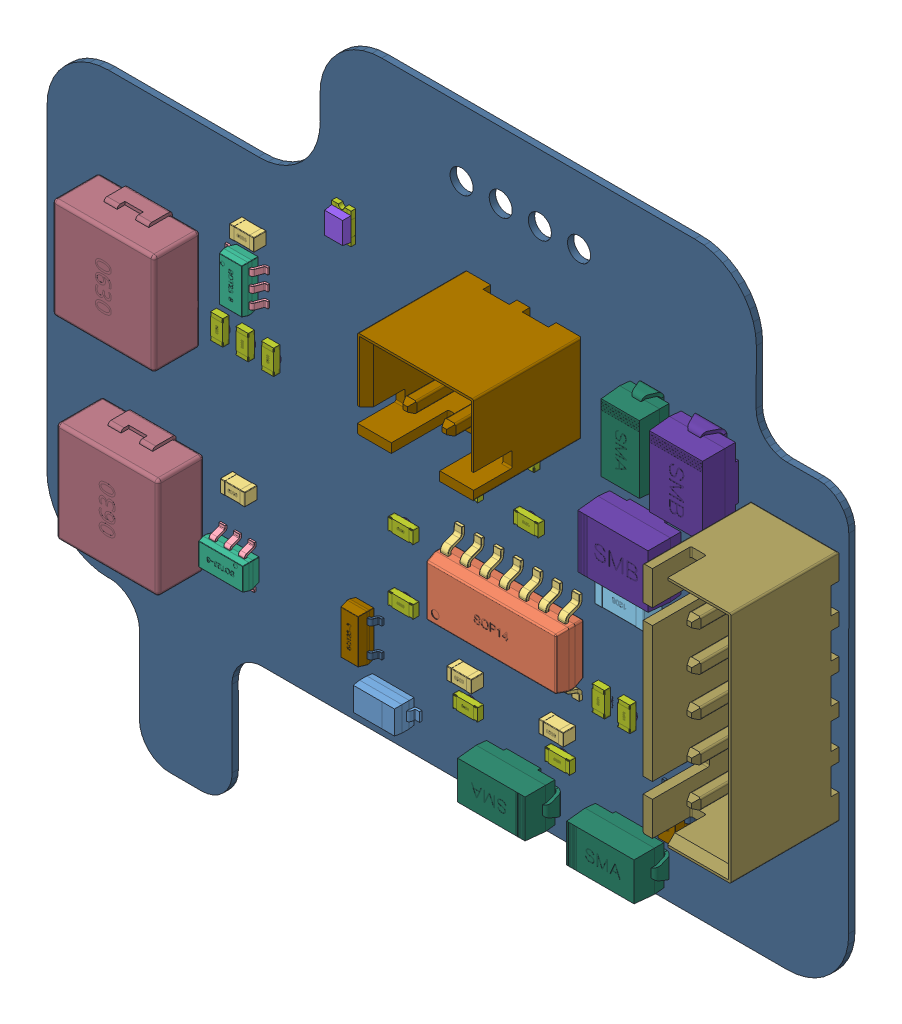
SolidWorks assembly 传感器电路板, configuration 默认. Lengths in mm.
Overall size (52.02 47.02 9.61).
221 component instances, 30 part files, 0 mates.
Components (placement in the parent):
- 传感器电路板.step-1: 传感器电路板.step [Default] at origin size (52.02 47.02 9.61)
  - U3.step-1: U3.step [Default] at origin size (8.7 6.01 1.9)
    - SOP14.step-1: SOP14.step [Default] at (4.699 -2.54 0) x (0 1 0) z (0 0 1) size (6.01 8.7 1.9)
      - LOGO__0.25.step-1: LOGO__0.25.step [Default] at (0.0116 0 0.095) x (0 -1 0) z (0 0 -1) size (0.75 0.87 0.01)
      - SOP14_____.step-1: SOP14_____.step [Default] at origin size (3.6 8.7 1.8)
      - ____1.8_______.step-1: ____1.8_______.step [Default] at (1.8 3.84 1) x (0 1 0) z (0 0 1) size (0.5 1.2 1.1)
      - ____1.8_______.step-2: ____1.8_______.step [Default] at (1.8 2.57 1) x (0 1 0) z (0 0 1) size (0.5 1.2 1.1)
      - ____1.8_______.step-3: ____1.8_______.step [Default] at (1.8 1.3 1) x (0 1 0) z (0 0 1) size (0.5 1.2 1.1)
      - ____1.8_______.step-4: ____1.8_______.step [Default] at (1.8 0.03 1) x (0 1 0) z (0 0 1) size (0.5 1.2 1.1)
      - ____1.8_______.step-5: ____1.8_______.step [Default] at (1.8 -1.24 1) x (0 1 0) z (0 0 1) size (0.5 1.2 1.1)
      - ____1.8_______.step-6: ____1.8_______.step [Default] at (1.8 -2.51 1) x (0 1 0) z (0 0 1) size (0.5 1.2 1.1)
      - ____1.8_______.step-7: ____1.8_______.step [Default] at (1.8 -3.78 1) x (0 1 0) z (0 0 1) size (0.5 1.2 1.1)
      - ____1.8_______.step-8: ____1.8_______.step [Default] at (-1.8 3.84 1) x (0 -1 0) z (0 0 1) size (0.5 1.2 1.1)
      - ____1.8_______.step-9: ____1.8_______.step [Default] at (-1.8 2.57 1) x (0 -1 0) z (0 0 1) size (0.5 1.2 1.1)
      - ____1.8_______.step-10: ____1.8_______.step [Default] at (-1.8 1.3 1) x (0 -1 0) z (0 0 1) size (0.5 1.2 1.1)
      - ____1.8_______.step-11: ____1.8_______.step [Default] at (-1.8 0.03 1) x (0 -1 0) z (0 0 1) size (0.5 1.2 1.1)
      - ____1.8_______.step-12: ____1.8_______.step [Default] at (-1.8 -1.24 1) x (0 -1 0) z (0 0 1) size (0.5 1.2 1.1)
      - ____1.8_______.step-13: ____1.8_______.step [Default] at (-1.8 -2.51 1) x (0 -1 0) z (0 0 1) size (0.5 1.2 1.1)
      - ____1.8_______.step-14: ____1.8_______.step [Default] at (-1.8 -3.78 1) x (0 -1 0) z (0 0 1) size (0.5 1.2 1.1)
  - U2.step-1: U2.step [Default] at origin size (2.81 3 1.18)
    - SOT23-6.step-1: SOT23-6.step [Default] at (-12.954 7.493 0) x (0 -1 0) z (0 0 1) size (3 2.81 1.18)
      - SOT23-5and6_____.step-1: SOT23-5and6_____.step [Default] at (-0.95 -0.8 0.675) x (-1 0 0) z (0 0 1) size (0.4 0.6 0.78)
      - SOT23-5and6_____.step-2: SOT23-5and6_____.step [Default] at (0 -0.8 0.675) x (-1 0 0) z (0 0 1) size (0.4 0.6 0.78)
      - SOT23-5and6_____.step-3: SOT23-5and6_____.step [Default] at (0.95 -0.8 0.675) x (-1 0 0) z (0 0 1) size (0.4 0.6 0.78)
      - SOT23-5and6_____.step-4: SOT23-5and6_____.step [Default] at (-0.95 0.8 0.675) size (0.4 0.6 0.78)
      - SOT23-5and6_____.step-5: SOT23-5and6_____.step [Default] at (0.95 0.8 0.675) size (0.4 0.6 0.78)
      - LOGO__0.15.step-1: LOGO__0.15.step [Default] at (0 -0.0167 0.0485) x (-1 0 0) z (0 0 -1) size (0.45 0.52 0)
      - SOT23-6-0.step-1: SOT23-6-0.step [Default] at origin size (3 1.6 1.1)
      - SOT23-5and6_____.step-6: SOT23-5and6_____.step [Default] at (0 0.8 0.675) size (0.4 0.6 0.78)
  - U1.step-1: U1.step [Default] at origin size (3 2.81 1.18)
    - SOT23-6.step-1: SOT23-6.step [Default] at (-13.589 -8.636 0) x (-1 0 0) z (0 0 1) size (3 2.81 1.18)
      - SOT23-5and6_____.step-1: SOT23-5and6_____.step [Default] at (-0.95 -0.8 0.675) x (-1 0 0) z (0 0 1) size (0.4 0.6 0.78)
      - SOT23-5and6_____.step-2: SOT23-5and6_____.step [Default] at (0 -0.8 0.675) x (-1 0 0) z (0 0 1) size (0.4 0.6 0.78)
      - SOT23-5and6_____.step-3: SOT23-5and6_____.step [Default] at (0.95 -0.8 0.675) x (-1 0 0) z (0 0 1) size (0.4 0.6 0.78)
      - SOT23-5and6_____.step-4: SOT23-5and6_____.step [Default] at (-0.95 0.8 0.675) size (0.4 0.6 0.78)
      - SOT23-5and6_____.step-5: SOT23-5and6_____.step [Default] at (0.95 0.8 0.675) size (0.4 0.6 0.78)
      - LOGO__0.15.step-1: LOGO__0.15.step [Default] at (0 -0.0167 0.0485) x (-1 0 0) z (0 0 -1) size (0.45 0.52 0)
      - SOT23-6-0.step-1: SOT23-6-0.step [Default] at origin size (3 1.6 1.1)
      - SOT23-5and6_____.step-6: SOT23-5and6_____.step [Default] at (0 0.8 0.675) size (0.4 0.6 0.78)
  - R18.step-1: R18.step [Default] at origin size (1.6 0.8 0.4)
    - R_0603.step-1: R_0603.step [Default] at (-2.667 -1.524 0) x (1 0 0) z (0 0 1) size (1.6 0.8 0.4)
      - R_0603-1.step-1: R_0603-1.step [Default] at origin size (1.6 0.8 0.4)
      - LOGO__.step-1: LOGO__.step [Default] at (0.0001 0.0322 -0.0016) x (-1 0 0) z (0 0 -1) size (0.48 0.55 0)
  - R17.step-1: R17.step [Default] at origin size (0.8 1.6 0.4)
    - R_0603.step-1: R_0603.step [Default] at (5.588 6.858 0) x (0 1 0) z (0 0 1) size (1.6 0.8 0.4)
      - R_0603-1.step-1: R_0603-1.step [Default] at origin size (1.6 0.8 0.4)
      - LOGO__.step-1: LOGO__.step [Default] at (0.0001 0.0322 -0.0016) x (-1 0 0) z (0 0 -1) size (0.48 0.55 0)
  - R16.step-1: R16.step [Default] at origin size (1.6 0.8 0.4)
    - R_0603.step-1: R_0603.step [Default] at (5.461 2.921 0) x (1 0 0) z (0 0 1) size (1.6 0.8 0.4)
      - R_0603-1.step-1: R_0603-1.step [Default] at origin size (1.6 0.8 0.4)
      - LOGO__.step-1: LOGO__.step [Default] at (0.0001 0.0322 -0.0016) x (-1 0 0) z (0 0 -1) size (0.48 0.55 0)
  - R15.step-1: R15.step [Default] at origin size (1.6 0.8 0.4)
    - R_0603.step-1: R_0603.step [Default] at (1.524 2.921 0) x (1 0 0) z (0 0 1) size (1.6 0.8 0.4)
      - R_0603-1.step-1: R_0603-1.step [Default] at origin size (1.6 0.8 0.4)
      - LOGO__.step-1: LOGO__.step [Default] at (0.0001 0.0322 -0.0016) x (-1 0 0) z (0 0 -1) size (0.48 0.55 0)
  - R14.step-1: R14.step [Default] at origin size (1.6 0.8 0.4)
    - R_0603.step-1: R_0603.step [Default] at (7.493 -9.398 0) x (1 0 0) z (0 0 1) size (1.6 0.8 0.4)
      - R_0603-1.step-1: R_0603-1.step [Default] at origin size (1.6 0.8 0.4)
      - LOGO__.step-1: LOGO__.step [Default] at (0.0001 0.0322 -0.0016) x (-1 0 0) z (0 0 -1) size (0.48 0.55 0)
  - R13.step-1: R13.step [Default] at origin size (0.8 1.6 0.4)
    - R_0603.step-1: R_0603.step [Default] at (10.16 -4.699 0) x (0 1 0) z (0 0 1) size (1.6 0.8 0.4)
      - R_0603-1.step-1: R_0603-1.step [Default] at origin size (1.6 0.8 0.4)
      - LOGO__.step-1: LOGO__.step [Default] at (0.0001 0.0322 -0.0016) x (-1 0 0) z (0 0 -1) size (0.48 0.55 0)
  - R12.step-1: R12.step [Default] at origin size (0.8 1.6 0.4)
    - R_0603.step-1: R_0603.step [Default] at (11.811 -4.699 0) x (0 -1 0) z (0 0 1) size (1.6 0.8 0.4)
      - R_0603-1.step-1: R_0603-1.step [Default] at origin size (1.6 0.8 0.4)
      - LOGO__.step-1: LOGO__.step [Default] at (0.0001 0.0322 -0.0016) x (-1 0 0) z (0 0 -1) size (0.48 0.55 0)
  - R11.step-1: R11.step [Default] at origin size (1.6 0.8 0.4)
    - R_0603.step-1: R_0603.step [Default] at (-2.667 -5.715 0) x (1 0 0) z (0 0 1) size (1.6 0.8 0.4)
      - R_0603-1.step-1: R_0603-1.step [Default] at origin size (1.6 0.8 0.4)
      - LOGO__.step-1: LOGO__.step [Default] at (0.0001 0.0322 -0.0016) x (-1 0 0) z (0 0 -1) size (0.48 0.55 0)
  - R10.step-1: R10.step [Default] at origin size (0.8 1.6 0.4)
    - R_0603.step-1: R_0603.step [Default] at (13.462 -4.699 0) x (0 -1 0) z (0 0 1) size (1.6 0.8 0.4)
      - R_0603-1.step-1: R_0603-1.step [Default] at origin size (1.6 0.8 0.4)
      - LOGO__.step-1: LOGO__.step [Default] at (0.0001 0.0322 -0.0016) x (-1 0 0) z (0 0 -1) size (0.48 0.55 0)
  - R9.step-1: R9.step [Default] at origin size (1.6 0.8 0.4)
    - R_0603.step-1: R_0603.step [Default] at (1.524 -9.398 0) x (1 0 0) z (0 0 1) size (1.6 0.8 0.4)
      - R_0603-1.step-1: R_0603-1.step [Default] at origin size (1.6 0.8 0.4)
      - LOGO__.step-1: LOGO__.step [Default] at (0.0001 0.0322 -0.0016) x (-1 0 0) z (0 0 -1) size (0.48 0.55 0)
  - R8.step-1: R8.step [Default] at origin size (0.8 1.6 0.4)
    - R_0603.step-1: R_0603.step [Default] at (16.891 -4.699 0) x (0 1 0) z (0 0 1) size (1.6 0.8 0.4)
      - R_0603-1.step-1: R_0603-1.step [Default] at origin size (1.6 0.8 0.4)
      - LOGO__.step-1: LOGO__.step [Default] at (0.0001 0.0322 -0.0016) x (-1 0 0) z (0 0 -1) size (0.48 0.55 0)
  - R7.step-1: R7.step [Default] at origin size (0.8 1.6 0.4)
    - R_0603.step-1: R_0603.step [Default] at (15.24 -4.699 0) x (0 1 0) z (0 0 1) size (1.6 0.8 0.4)
      - R_0603-1.step-1: R_0603-1.step [Default] at origin size (1.6 0.8 0.4)
      - LOGO__.step-1: LOGO__.step [Default] at (0.0001 0.0322 -0.0016) x (-1 0 0) z (0 0 -1) size (0.48 0.55 0)
  - R6.step-1: R6.step [Default] at origin size (0.8 1.6 0.4)
    - R_0603.step-1: R_0603.step [Default] at (-14.605 3.81 0) x (0 -1 0) z (0 0 1) size (1.6 0.8 0.4)
      - R_0603-1.step-1: R_0603-1.step [Default] at origin size (1.6 0.8 0.4)
      - LOGO__.step-1: LOGO__.step [Default] at (0.0001 0.0322 -0.0016) x (-1 0 0) z (0 0 -1) size (0.48 0.55 0)
  - R5.step-1: R5.step [Default] at origin size (0.8 1.6 0.4)
    - R_0603.step-1: R_0603.step [Default] at (-12.954 3.81 0) x (0 -1 0) z (0 0 1) size (1.6 0.8 0.4)
      - R_0603-1.step-1: R_0603-1.step [Default] at origin size (1.6 0.8 0.4)
      - LOGO__.step-1: LOGO__.step [Default] at (0.0001 0.0322 -0.0016) x (-1 0 0) z (0 0 -1) size (0.48 0.55 0)
  - R4.step-1: R4.step [Default] at origin size (0.8 1.6 0.4)
    - R_0603.step-1: R_0603.step [Default] at (-11.303 3.81 0) x (0 -1 0) z (0 0 1) size (1.6 0.8 0.4)
      - R_0603-1.step-1: R_0603-1.step [Default] at origin size (1.6 0.8 0.4)
      - LOGO__.step-1: LOGO__.step [Default] at (0.0001 0.0322 -0.0016) x (-1 0 0) z (0 0 -1) size (0.48 0.55 0)
  - R3.step-1: R3.step [Default] at origin size (1.6 0.8 0.4)
    - R_0603.step-1: R_0603.step [Default] at (-16.256 -5.969 -0.4115) x (1 0 0) z (0 0 -1) size (1.6 0.8 0.4)
      - R_0603-1.step-1: R_0603-1.step [Default] at origin size (1.6 0.8 0.4)
      - LOGO__.step-1: LOGO__.step [Default] at (0.0001 0.0322 -0.0016) x (-1 0 0) z (0 0 -1) size (0.48 0.55 0)
  - R2.step-1: R2.step [Default] at origin size (1.6 0.8 0.4)
    - R_0603.step-1: R_0603.step [Default] at (-16.256 -7.747 -0.4115) x (1 0 0) z (0 0 -1) size (1.6 0.8 0.4)
      - R_0603-1.step-1: R_0603-1.step [Default] at origin size (1.6 0.8 0.4)
      - LOGO__.step-1: LOGO__.step [Default] at (0.0001 0.0322 -0.0016) x (-1 0 0) z (0 0 -1) size (0.48 0.55 0)
  - R1.step-1: R1.step [Default] at origin size (1.6 0.8 0.4)
    - R_0603.step-1: R_0603.step [Default] at (-16.256 -9.652 -0.4115) x (-1 0 0) z (0 0 -1) size (1.6 0.8 0.4)
      - R_0603-1.step-1: R_0603-1.step [Default] at origin size (1.6 0.8 0.4)
      - LOGO__.step-1: LOGO__.step [Default] at (0.0001 0.0322 -0.0016) x (-1 0 0) z (0 0 -1) size (0.48 0.55 0)
  - Q2.step-1: Q2.step [Default] at origin size (2.4 3 1.05)
    - SOT23-3.step-1: SOT23-3.step [Default] at (15.24 -8.382 0) x (0 -1 0) z (0 0 1) size (3 2.4 1.05)
      - SOT23-3-2.step-1: SOT23-3-2.step [Default] at origin size (3 1.3 1)
      - SOT23-3_____.step-1: SOT23-3_____.step [Default] at (0 0.5461 0.475) size (0.4 0.65 0.55)
      - SOT23-3_____.step-2: SOT23-3_____.step [Default] at (-0.95 -0.5461 0.475) x (-1 0 0) z (0 0 1) size (0.4 0.65 0.55)
      - SOT23-3_____.step-3: SOT23-3_____.step [Default] at (0.95 -0.5461 0.475) x (-1 0 0) z (0 0 1) size (0.4 0.65 0.55)
      - LOGO__0.15-3.step-1: LOGO__0.15-3.step [Default] at (0 -0.0163 0.0485) x (-1 0 0) z (0 0 -1) size (0.45 0.52 0)
  - Q1.step-1: Q1.step [Default] at origin size (2.4 3 1.05)
    - SOT23-3.step-1: SOT23-3.step [Default] at (-5.334 -8.509 0) x (0 1 0) z (0 0 1) size (3 2.4 1.05)
      - SOT23-3-2.step-1: SOT23-3-2.step [Default] at origin size (3 1.3 1)
      - SOT23-3_____.step-1: SOT23-3_____.step [Default] at (0 0.5461 0.475) size (0.4 0.65 0.55)
      - SOT23-3_____.step-2: SOT23-3_____.step [Default] at (-0.95 -0.5461 0.475) x (-1 0 0) z (0 0 1) size (0.4 0.65 0.55)
      - SOT23-3_____.step-3: SOT23-3_____.step [Default] at (0.95 -0.5461 0.475) x (-1 0 0) z (0 0 1) size (0.4 0.65 0.55)
      - LOGO__0.15-3.step-1: LOGO__0.15-3.step [Default] at (0 -0.0163 0.0485) x (-1 0 0) z (0 0 -1) size (0.45 0.52 0)
  - P2.step-1: P2.step [Default] at origin size (5.7 15.16 9.5)
    - XH2.54-5P.step-1: XH2.54-5P.step [Default] at (22.098 -1.524 0.03) x (0 1 0) z (1 0 0) size (15.16 9.5 5.7)
      - LOGO__-4.step-1: LOGO__-4.step [Default] at (-1.7013 -0.001 0) x (0 0 1) z (0 -1 0) size (0.9 1.04 0.01)
      - XH2.54-5P-5.step-1: XH2.54-5P-5.step [Default] at origin size (15.16 9.5 5.7)
  - L2.step-1: L2.step [Default] at origin size (6.6 6.95 3.03)
    - SMD-0630.step-1: SMD-0630.step [Default] at (-19.304 5.207 0) x (0 -1 0) z (0 0 1) size (6.95 6.6 3.03)
      - SMD-0630-6.step-1: SMD-0630-6.step [Default] at origin size (6.95 6.6 3.03)
      - LOGO__0.5.step-1: LOGO__0.5.step [Default] at (0 0.0017 0.04) size (1.5 1.73 0.01)
  - L1.step-1: L1.step [Default] at origin size (6.6 6.95 3.03)
    - SMD-0630.step-1: SMD-0630.step [Default] at (-19.05 -7.239 0) x (0 1 0) z (0 0 1) size (6.95 6.6 3.03)
      - SMD-0630-6.step-1: SMD-0630-6.step [Default] at origin size (6.95 6.6 3.03)
      - LOGO__0.5.step-1: LOGO__0.5.step [Default] at (0 0.0017 0.04) size (1.5 1.73 0.01)
  - D8.step-1: D8.step [Default] at origin size (5.12 2.6 2.11)
    - SMA.step-1: SMA.step [Default] at (-19.0271 4.9529 -0.4615) x (-1 0 0) z (0 0 -1) size (5.12 2.6 2.11)
      - SMA-7.step-1: SMA-7.step [Default] at origin size (5.12 2.6 2.1)
      - LOGO______.__.step-1: LOGO______.__.step [Default] at (0.0018 0.0048 -0.003) x (-1 0 0) z (0 0 -1) size (0.9 1.04 0.01)
  - D7.step-1: D7.step [Default] at origin size (2.6 5.12 2.11)
    - SMA.step-1: SMA.step [Default] at (-22.4789 -7.2161 -0.4615) x (0 -1 0) z (0 0 -1) size (5.12 2.6 2.11)
      - SMA-7.step-1: SMA-7.step [Default] at origin size (5.12 2.6 2.1)
      - LOGO______.__.step-1: LOGO______.__.step [Default] at (0.0018 0.0048 -0.003) x (-1 0 0) z (0 0 -1) size (0.9 1.04 0.01)
  - D6.step-1: D6.step [Default] at origin size (5.31 3.6 2.31)
    - SMB.step-1: SMB.step [Default] at (13.0581 5.5879 0.05) x (1 0 0) z (0 0 1) size (5.31 3.6 2.31)
      - SMB-8.step-1: SMB-8.step [Default] at origin size (5.31 3.6 2.3)
      - LOGO______.__-9.step-1: LOGO______.__-9.step [Default] at (-0.0044 0 -0.003) x (-1 0 0) z (0 0 -1) size (0.9 1.04 0.01)
  - D5.step-1: D5.step [Default] at origin size (3.7 1.6 1.27)
    - SOD123.step-1: SOD123.step [Default] at (-3.5309 -11.6339 0) x (1 0 0) z (0 -1 0) size (3.7 1.27 1.6)
  - D4.step-1: D4.step [Default] at origin size (5.12 2.6 2.11)
    - SMA.step-1: SMA.step [Default] at (12.0421 -11.9381 0.05) x (1 0 0) z (0 0 1) size (5.12 2.6 2.11)
      - SMA-7.step-1: SMA-7.step [Default] at origin size (5.12 2.6 2.1)
      - LOGO______.__.step-1: LOGO______.__.step [Default] at (0.0018 0.0048 -0.003) x (-1 0 0) z (0 0 -1) size (0.9 1.04 0.01)
  - D3.step-1: D3.step [Default] at origin size (5.12 2.6 2.11)
    - SMA.step-1: SMA.step [Default] at (4.9759 -11.9379 0.05) x (-1 0 0) z (0 0 1) size (5.12 2.6 2.11)
      - SMA-7.step-1: SMA-7.step [Default] at origin size (5.12 2.6 2.1)
      - LOGO______.__.step-1: LOGO______.__.step [Default] at (0.0018 0.0048 -0.003) x (-1 0 0) z (0 0 -1) size (0.9 1.04 0.01)
  - D2.step-1: D2.step [Default] at origin size (3.6 5.31 2.31)
    - SMB.step-1: SMB.step [Default] at (17.1449 11.8339 0.05) x (0 -1 0) z (0 0 1) size (5.31 3.6 2.31)
      - SMB-8.step-1: SMB-8.step [Default] at origin size (5.31 3.6 2.3)
      - LOGO______.__-9.step-1: LOGO______.__-9.step [Default] at (-0.0044 0 -0.003) x (-1 0 0) z (0 0 -1) size (0.9 1.04 0.01)
  - D1.step-1: D1.step [Default] at origin size (2.6 5.12 2.11)
    - SMA.step-1: SMA.step [Default] at (13.3349 11.9609 0.05) x (0 -1 0) z (0 0 1) size (5.12 2.6 2.11)
      - SMA-7.step-1: SMA-7.step [Default] at origin size (5.12 2.6 2.1)
      - LOGO______.__.step-1: LOGO______.__.step [Default] at (0.0018 0.0048 -0.003) x (-1 0 0) z (0 0 -1) size (0.9 1.04 0.01)
  - C10.step-1: C10.step [Default] at origin size (1.6 0.82 0.82)
    - C_0603.step-1: C_0603.step [Default] at (7.493 -7.62 0) x (-1 0 0) z (0 0 1) size (1.6 0.82 0.82)
      - LOGO__-10.step-1: LOGO__-10.step [Default] at (0 0.0171 -0.0006) x (-1 0 0) z (0 0 -1) size (0.51 0.59 0)
      - C_0603-11.step-1: C_0603-11.step [Default] at origin size (1.6 0.82 0.82)
  - C9.step-1: C9.step [Default] at origin size (1.6 0.82 0.82)
    - C_0603.step-1: C_0603.step [Default] at (1.524 -7.62 0) x (1 0 0) z (0 0 1) size (1.6 0.82 0.82)
      - LOGO__-10.step-1: LOGO__-10.step [Default] at (0 0.0171 -0.0006) x (-1 0 0) z (0 0 -1) size (0.51 0.59 0)
      - C_0603-11.step-1: C_0603-11.step [Default] at origin size (1.6 0.82 0.82)
  - C8.step-1: C8.step [Default] at origin size (3.2 1.62 1.22)
    - C_1206.step-1: C_1206.step [Default] at (-19.558 1.778 -0.4115) x (1 0 0) z (0 0 -1) size (3.2 1.62 1.22)
      - LOGO__-12.step-1: LOGO__-12.step [Default] at (0 0.0171 -0.0006) x (-1 0 0) z (0 0 -1) size (0.51 0.59 0)
      - C_1206-13.step-1: C_1206-13.step [Default] at origin size (3.2 1.62 1.22)
  - C7.step-1: C7.step [Default] at origin size (1.62 3.2 1.22)
    - C_1206.step-1: C_1206.step [Default] at (-19.431 -7.874 -0.4115) x (0 -1 0) z (0 0 -1) size (3.2 1.62 1.22)
      - LOGO__-12.step-1: LOGO__-12.step [Default] at (0 0.0171 -0.0006) x (-1 0 0) z (0 0 -1) size (0.51 0.59 0)
      - C_1206-13.step-1: C_1206-13.step [Default] at origin size (3.2 1.62 1.22)
  - C6.step-1: C6.step [Default] at origin size (3.2 1.62 1.22)
    - C_1206.step-1: C_1206.step [Default] at (12.319 2.286 0) x (-1 0 0) z (0 0 1) size (3.2 1.62 1.22)
      - LOGO__-12.step-1: LOGO__-12.step [Default] at (0 0.0171 -0.0006) x (-1 0 0) z (0 0 -1) size (0.51 0.59 0)
      - C_1206-13.step-1: C_1206-13.step [Default] at origin size (3.2 1.62 1.22)
  - C5.step-1: C5.step [Default] at origin size (1.6 0.82 0.82)
    - C_0603.step-1: C_0603.step [Default] at (-12.573 10.16 0) x (1 0 0) z (0 0 1) size (1.6 0.82 0.82)
      - LOGO__-10.step-1: LOGO__-10.step [Default] at (0 0.0171 -0.0006) x (-1 0 0) z (0 0 -1) size (0.51 0.59 0)
      - C_0603-11.step-1: C_0603-11.step [Default] at origin size (1.6 0.82 0.82)
  - C4.step-1: C4.step [Default] at origin size (1.62 3.2 1.22)
    - C_1206.step-1: C_1206.step [Default] at (18.923 7.493 -0.4115) x (0 -1 0) z (0 0 -1) size (3.2 1.62 1.22)
      - LOGO__-12.step-1: LOGO__-12.step [Default] at (0 0.0171 -0.0006) x (-1 0 0) z (0 0 -1) size (0.51 0.59 0)
      - C_1206-13.step-1: C_1206-13.step [Default] at origin size (3.2 1.62 1.22)
  - C3.step-1: C3.step [Default] at origin size (3.2 1.62 1.22)
    - C_1206.step-1: C_1206.step [Default] at (-19.685 8.128 -0.4115) x (-1 0 0) z (0 0 -1) size (3.2 1.62 1.22)
      - LOGO__-12.step-1: LOGO__-12.step [Default] at (0 0.0171 -0.0006) x (-1 0 0) z (0 0 -1) size (0.51 0.59 0)
      - C_1206-13.step-1: C_1206-13.step [Default] at origin size (3.2 1.62 1.22)
  - C2.step-1: C2.step [Default] at origin size (3.2 1.62 1.22)
    - C_1206.step-1: C_1206.step [Default] at (-19.685 11.049 -0.4115) x (-1 0 0) z (0 0 -1) size (3.2 1.62 1.22)
      - LOGO__-12.step-1: LOGO__-12.step [Default] at (0 0.0171 -0.0006) x (-1 0 0) z (0 0 -1) size (0.51 0.59 0)
      - C_1206-13.step-1: C_1206-13.step [Default] at origin size (3.2 1.62 1.22)
  - C1.step-1: C1.step [Default] at origin size (1.6 0.82 0.82)
    - C_0603.step-1: C_0603.step [Default] at (-13.1699 -4.445 0) x (-1 0 0) z (0 0 1) size (1.6 0.82 0.82)
      - LOGO__-10.step-1: LOGO__-10.step [Default] at (0 0.0171 -0.0006) x (-1 0 0) z (0 0 -1) size (0.51 0.59 0)
      - C_0603-11.step-1: C_0603-11.step [Default] at origin size (1.6 0.82 0.82)
  - LED1.step-1: LED1.step [Default] at origin size (1.25 2 0.81)
    - LED_0805-R.step-1: LED_0805-R.step [Default] at (-6.604 13.716 0) x (0 -1 0) z (0 0 1) size (2 1.25 0.67)
      - LOGO__-14.step-1: LOGO__-14.step [Default] at (0 0.0303 -0.002) x (-1 0 0) z (0 0 -1) size (0.6 0.69 0)
      - LED_0805-R-15.step-1: LED_0805-R-15.step [Default] at origin size (2 1.25 0.67)
    - LED_0805______.step-1: LED_0805______.step [Default] at (-6.604 13.716 0) x (0 1 0) z (0 0 1) size (1.5 1.25 0.5)
  - R19.step-1: R19.step [Default] at origin size (1.6 0.8 0.4)
    - R_0603.step-1: R_0603.step [Default] at (-1.651 16.256 -0.4115) x (-1 0 0) z (0 0 -1) size (1.6 0.8 0.4)
      - R_0603-1.step-1: R_0603-1.step [Default] at origin size (1.6 0.8 0.4)
      - LOGO__.step-1: LOGO__.step [Default] at (0.0001 0.0322 -0.0016) x (-1 0 0) z (0 0 -1) size (0.48 0.55 0)
  - P4.step-1: P4.step [Default] at origin size (7.54 5.7 9.5)
    - XH2.54-2P.step-1: XH2.54-2P.step [Default] at (6.223 11.557 0.05) x (-1 0 0) z (0 1 0) size (7.54 9.5 5.7)
      - XH2.54-2P-16.step-1: XH2.54-2P-16.step [Default] at origin size (7.54 9.5 5.7)
      - LOGO__-17.step-1: LOGO__-17.step [Default] at (-1.7013 -0.001 0) x (0 0 1) z (0 -1 0) size (0.9 1.04 0.01)
  - Board.step-1: Board.step [Default] at (0 0 -0.4115) size (52.02 47.02 0.41)
